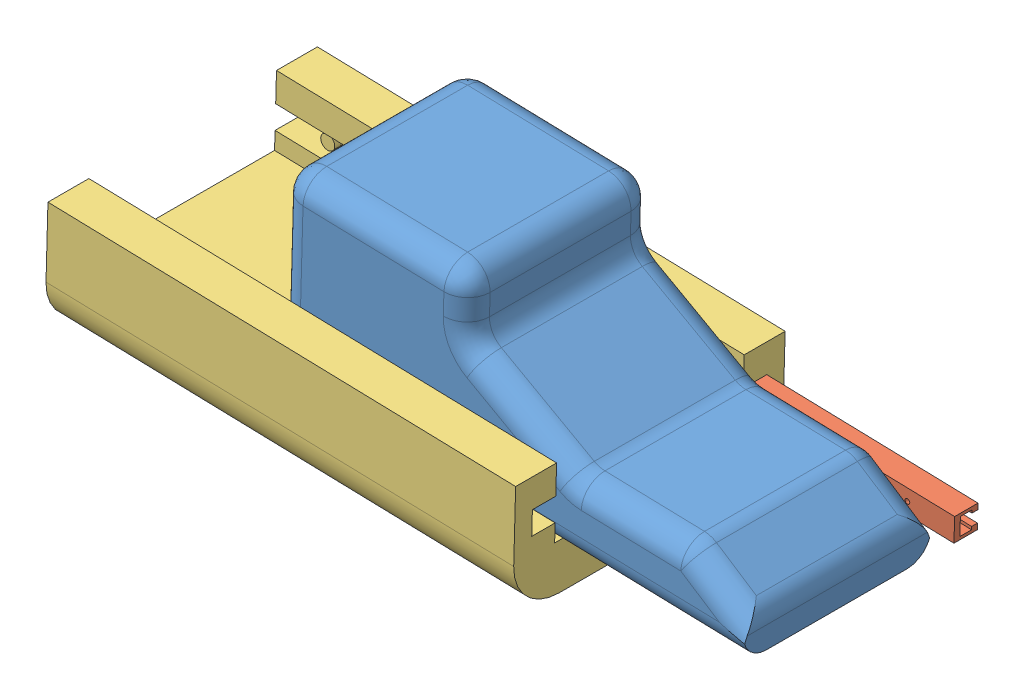
SolidWorks assembly Assem1, configuration Default. Lengths in mm.
Overall size (369.85 128.13 146.38).
3 component instances, 3 part files, 5 mates.
Components (placement in the parent):
- Shoe-1: Shoe [Default] at (5.3336 230.1735 206.0737) x (0.999646 -0.02659 0.000014) z (0.000014 0.001074 0.999999) size (254 101.6 101.6)
- RailModule1-2: RailModule1 [Default] at (18.5388 254.9621 104.4468) x (0.999646 -0.02659 0.000014) z (0.02659 0.999646 -0.001074) size (254 12.7 12.7)
- ShoeSole1-1: ShoeSole1 [Default] at (-97.3949 210.519 228.5753) x (0.999646 -0.02659 0.000014) z (0.000014 0.001074 0.999999) size (254 63.5 146.3)
Mates (geometry in assembly coordinates):
- Coincident8: coincident anti-aligned: plane of Shoe-1 through (6.3452 268.151 104.4328) normal (-0.000014 -0.001074 -0.999999); plane of RailModule1-2 through (18.5388 254.9621 104.4468) normal (0.000014 0.001074 0.999999)
- Coincident9: coincident aligned: line of Shoe-1 through (246.2241 236.2013 104.4637) axis (-0.999646 0.02659 -0.000014); line of RailModule1-2 through (272.1113 235.5127 104.4641) axis (-0.999646 0.02659 -0.000014)
- Coincident10: coincident aligned: line of Shoe-1 through (18.2011 242.2666 104.4605) axis (0.02659 0.999646 -0.001074); line of RailModule1-2 through (18.2011 242.2666 104.4605) axis (0.02659 0.999646 -0.001074)
- Coincident13: coincident anti-aligned: plane of RailModule1-2 through (18.201 242.2529 91.7605) normal (-0.02659 -0.999646 0.001074); plane of ShoeSole1-1 through (157.4426 238.5628 104.4624) normal (0.02659 0.999646 -0.001074)
- Coincident17: coincident anti-aligned: plane of RailModule1-2 through (18.5387 254.9485 91.7468) normal (-0.000014 -0.001074 -0.999999); plane of ShoeSole1-1 through (157.4425 238.5492 91.7625) normal (0.000014 0.001074 0.999999)
